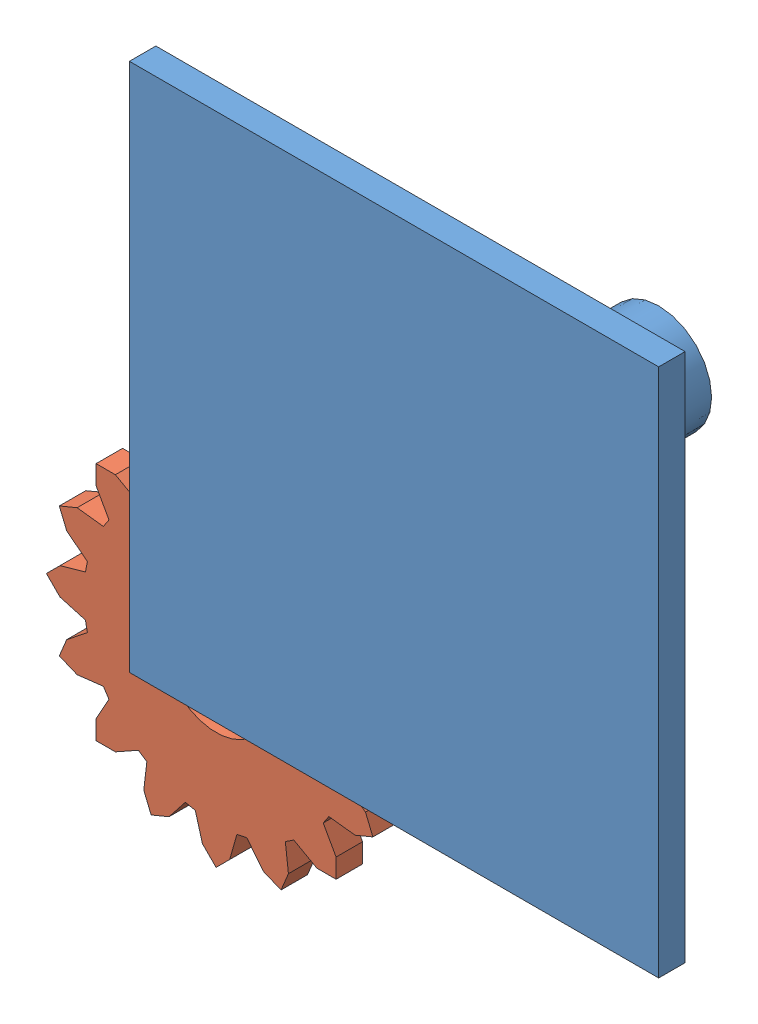
SolidWorks assembly Assem1, configuration Default. Lengths in mm.
Overall size (241.37 257.43 100).
3 component instances, 2 part files, 4 mates.
Components (placement in the parent):
- plane_and_cylinder-1: plane_and_cylinder [Default] at (39.6496 123.4124 159.0523) size (200 200 100)
- gear1-1: gear1 [Default] at (37.2237 90.5283 149.0523) size (128.25 128.25 10)
- gear1-2: gear1 [Default] at (-40.016 -2.7708 149.0523) size (128.25 128.25 10)
Mates (geometry in assembly coordinates):
- Coincident1: coincident anti-aligned: plane of plane_and_cylinder-1 through (39.6496 123.4124 159.0523) normal (0 0 -1); plane of gear1-1 through (37.2237 90.5283 159.0523) normal (0 0 1)
- Concentric1: concentric anti-aligned: cylinder of plane_and_cylinder-1 through (37.2237 90.5283 69.0523) axis (0 0 1) radius 20; cylinder of gear1-1 through (37.2237 90.5283 159.0523) axis (0 0 -1) radius 20
- Coincident2: coincident anti-aligned: plane of plane_and_cylinder-1 through (39.6496 123.4124 159.0523) normal (0 0 -1); plane of gear1-2 through (-40.016 -2.7708 159.0523) normal (0 0 1)
- Concentric2: concentric aligned: circle of gear1-2
